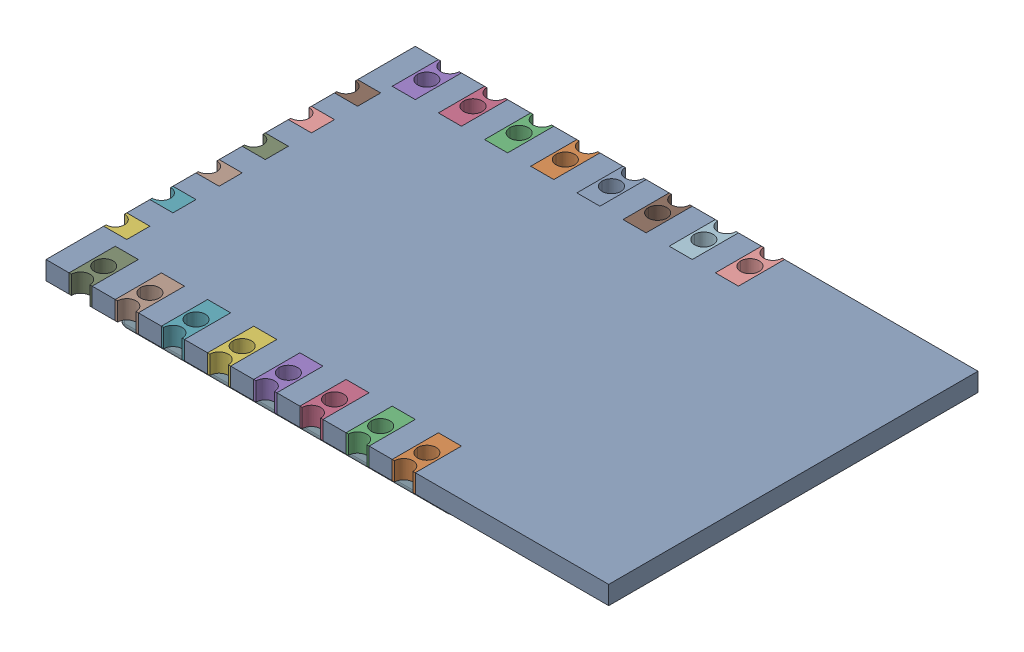
SolidWorks assembly 0411-2, configuration 默认. Lengths in mm.
Overall size (24.38 3.05 16).
26 component instances, 6 part files, 0 mates.
Components (placement in the parent):
- User_Library-ESP8266-12E_PCB1-1: User_Library-ESP8266-12E_PCB1 [默认] x (-1 0 0) z (0 0 1) size (24.38 0.8 16)
- User_Library-ESP8266-12E_Pin1-1: User_Library-ESP8266-12E_Pin1 [默认] at (3.31 0 8) x (-1 0 0) z (0 -1 0) size (1 2 0.8)
- User_Library-ESP8266-12E_Pin1-2: User_Library-ESP8266-12E_Pin1 [默认] at (1.31 0 8) x (-1 0 0) z (0 -1 0) size (1 2 0.8)
- User_Library-ESP8266-12E_Pin1-3: User_Library-ESP8266-12E_Pin1 [默认] at (-0.69 0 8) x (-1 0 0) z (0 -1 0) size (1 2 0.8)
- User_Library-ESP8266-12E_Pin1-4: User_Library-ESP8266-12E_Pin1 [默认] at (-2.69 0 8) x (-1 0 0) z (0 -1 0) size (1 2 0.8)
- User_Library-ESP8266-12E_Pin1-5: User_Library-ESP8266-12E_Pin1 [默认] at (-4.69 0 8) x (-1 0 0) z (0 -1 0) size (1 2 0.8)
- User_Library-ESP8266-12E_Pin1-6: User_Library-ESP8266-12E_Pin1 [默认] at (-6.69 0 8) x (-1 0 0) z (0 -1 0) size (1 2 0.8)
- User_Library-ESP8266-12E_Pin1-7: User_Library-ESP8266-12E_Pin1 [默认] at (-8.69 0 8) x (-1 0 0) z (0 -1 0) size (1 2 0.8)
- User_Library-ESP8266-12E_Pin1-8: User_Library-ESP8266-12E_Pin1 [默认] at (-10.69 0 8) x (-1 0 0) z (0 -1 0) size (1 2 0.8)
- User_Library-ESP8266-12E_Pin1-9: User_Library-ESP8266-12E_Pin1 [默认] at (3.31 0 -8) x (1 0 0) z (0 -1 0) size (1 2 0.8)
- User_Library-ESP8266-12E_Pin1-10: User_Library-ESP8266-12E_Pin1 [默认] at (-0.69 0 -8) x (1 0 0) z (0 -1 0) size (1 2 0.8)
- User_Library-ESP8266-12E_Pin1-11: User_Library-ESP8266-12E_Pin1 [默认] at (1.31 0 -8) x (1 0 0) z (0 -1 0) size (1 2 0.8)
- User_Library-ESP8266-12E_Pin1-12: User_Library-ESP8266-12E_Pin1 [默认] at (-2.69 0 -8) x (1 0 0) z (0 -1 0) size (1 2 0.8)
- User_Library-ESP8266-12E_Pin1-13: User_Library-ESP8266-12E_Pin1 [默认] at (-4.69 0 -8) x (1 0 0) z (0 -1 0) size (1 2 0.8)
- User_Library-ESP8266-12E_Pin1-14: User_Library-ESP8266-12E_Pin1 [默认] at (-6.69 0 -8) x (1 0 0) z (0 -1 0) size (1 2 0.8)
- User_Library-ESP8266-12E_Pin1-15: User_Library-ESP8266-12E_Pin1 [默认] at (-8.69 0 -8) x (1 0 0) z (0 -1 0) size (1 2 0.8)
- User_Library-ESP8266-12E_Pin1-16: User_Library-ESP8266-12E_Pin1 [默认] at (-10.69 0 -8) x (1 0 0) z (0 -1 0) size (1 2 0.8)
- User_Library-ESP8266-12E_Pin2-1: User_Library-ESP8266-12E_Pin2 [默认] at (-12.19 0 5) x (0 0 1) z (0 1 0) size (1 1 0.8)
- User_Library-ESP8266-12E_Pin2-2: User_Library-ESP8266-12E_Pin2 [默认] at (-12.19 0 3) x (0 0 -1) z (0 -1 0) size (1 1 0.8)
- User_Library-ESP8266-12E_Pin2-3: User_Library-ESP8266-12E_Pin2 [默认] at (-12.19 0 1) x (0 0 1) z (0 1 0) size (1 1 0.8)
- User_Library-ESP8266-12E_Pin2-4: User_Library-ESP8266-12E_Pin2 [默认] at (-12.19 0 -1) x (0 0 1) z (0 1 0) size (1 1 0.8)
- User_Library-ESP8266-12E_Pin2-5: User_Library-ESP8266-12E_Pin2 [默认] at (-12.19 0 -3) x (0 0 1) z (0 1 0) size (1 1 0.8)
- User_Library-ESP8266-12E_Pin2-6: User_Library-ESP8266-12E_Pin2 [默认] at (-12.19 0 -5) x (0 0 1) z (0 1 0) size (1 1 0.8)
- User_Library-ESP8266-12E_Lid-1: User_Library-ESP8266-12E_Lid [默认] at (-3.84 -1.5 0.25) x (0 0 -1) z (0 -1 0) size (11.5 14.5 2.25)
- User_Library-ESP8266-12E_Antenne-1: User_Library-ESP8266-12E_Antenne [默认] at (4.99 -0.425 6) x (0 0 -1) z (0 -1 0) size (12.3 7 0.05)
- User_Library-ESP8266-12E_Surface_Mount_Chip_LED_3.2x1.6mm-1: User_Library-ESP8266-12E_Surface_Mount_Chip_LED_3.2x1.6mm [默认] at (6.19 -0.41 -7.5) x (0 0 1) z (0 -1 0) size (3.2 1.6 1.13)
